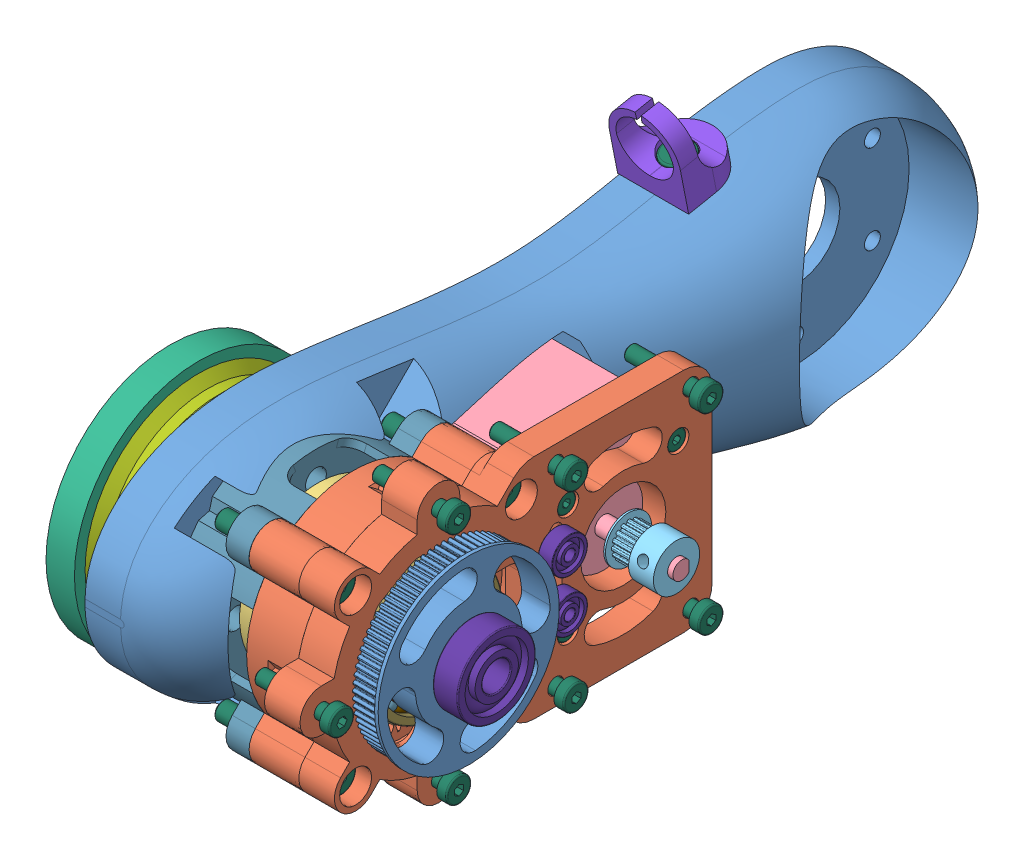
SolidWorks assembly Gelenk_1_V2.0, configuration Standard. Lengths in mm.
Overall size (92 93.85 230.1).
161 component instances, 44 part files, 23 mates.
Components (placement in the parent):
- Gelenk_1_Frame_2.0-2: Gelenk_1_Frame_2.0 [Standard] at origin size (47.61 72.17 230.1)
- G1_Strain_Wave-1: G1_Strain_Wave [Standard] at (47 0 150) x (0 0 -1) z (1 0 0) size (116 78 74.5)
  - G1_Circular_Spline-1: G1_Circular_Spline [Standard] at origin size (116 78 11.48)
  - G1_Flex_Spline-1: G1_Flex_Spline [Standard] at (0 0 -7.5) size (48 48 20)
  - 06153436-1: 06153436 [Default] at (0 0 -32) x (-0.516452 0.856316 0) z (0.856316 0.516452 0) size (37 7 37)
    - 06153436_01-1: 06153436_01 [Default] at origin size (3.6 3.6 3.6)
    - 06153436_02-1: 06153436_02 [Default] at origin size (3.6 3.6 3.6)
    - 06153436_03-1: 06153436_03 [Default] at origin size (3.6 3.6 3.6)
    - 06153436_04-1: 06153436_04 [Default] at origin size (3.6 3.6 3.6)
    - 06153436_05-1: 06153436_05 [Default] at origin size (3.6 3.6 3.6)
    - 06153436_06-1: 06153436_06 [Default] at origin size (3.6 3.6 3.6)
    - 06153436_07-1: 06153436_07 [Default] at origin size (3.6 3.6 3.6)
    - 06153436_08-1: 06153436_08 [Default] at origin size (3.6 3.6 3.6)
    - 06153436_09-1: 06153436_09 [Default] at origin size (3.6 3.6 3.6)
    - 06153436_10-1: 06153436_10 [Default] at origin size (3.6 3.6 3.6)
    - 06153436_11-1: 06153436_11 [Default] at origin size (3.6 3.6 3.6)
    - 06153436_12-1: 06153436_12 [Default] at origin size (3.6 3.6 3.6)
    - 06153436_13-1: 06153436_13 [Default] at origin size (3.6 3.6 3.6)
    - 06153436_14-1: 06153436_14 [Default] at origin size (3.6 3.6 3.6)
    - 06153436_15-1: 06153436_15 [Default] at origin size (3.6 3.6 3.6)
    - 06153436_16-1: 06153436_16 [Default] at origin size (3.6 3.6 3.6)
    - 06153436_17-1: 06153436_17 [Default] at origin size (3.6 3.6 3.6)
    - 06153436_18-1: 06153436_18 [Default] at origin size (3.6 3.6 3.6)
    - 06153436_19-1: 06153436_19 [Default] at origin size (3.6 3.6 3.6)
    - 06153436_20-1: 06153436_20 [Default] at origin size (3.6 3.6 3.6)
    - 06153436_21-1: 06153436_21 [Default] at origin size (3.6 3.6 3.6)
    - 06153436_22-1: 06153436_22 [Default] at origin size (3.6 3.6 3.6)
    - 06153436_23-1: 06153436_23 [Default] at origin size (3.6 3.6 3.6)
    - 06153436_24-1: 06153436_24 [Default] at origin size (3.6 3.6 3.6)
    - 06153436_25-1: 06153436_25 [Default] at origin size (3.6 3.6 3.6)
    - 06153436_26-1: 06153436_26 [Default] at origin size (29.2 7 29.2)
    - 06153436_27-1: 06153436_27 [Default] at origin size (37 7 37)
  - G1_Strain_Wave_Kupplung-1: G1_Strain_Wave_Kupplung [Standard] at (0 0 -35.5) x (-1 0 0) z (0 0 -1) size (26.9 26.9 20)
  - G1_Circular_Spline_Gehaeuse-1: G1_Circular_Spline_Gehaeuse [Standard] at (0 0 -20) size (60 60 22)
  - socket head thin cap screw_din-5: socket head thin cap screw_din [DIN 7984 - M5 x 30 --- 16N] at (23.3345 23.3345 -1.5) x (0 0 -1) z (1 0 0) size (33.5 8.5 8.5)
  - hex nut style 1 gradeab_din-1: hex nut style 1 gradeab_din [Hexagon Nut ISO 4032 - M5 - W - N] at (23.3345 23.3345 -23) x (0.965926 0.258819 0) z (0 0 1) size (8 9.24 4.7)
  - socket head thin cap screw_din-6: socket head thin cap screw_din [DIN 7984 - M5 x 30 --- 16N] at (-23.3345 23.3345 -1.5) x (0 0 -1) z (0 1 0) size (33.5 8.5 8.5)
  - socket head thin cap screw_din-7: socket head thin cap screw_din [DIN 7984 - M5 x 30 --- 16N] at (-23.3345 -23.3345 -1.5) x (0 0 -1) z (-1 0 0) size (33.5 8.5 8.5)
  - socket head thin cap screw_din-8: socket head thin cap screw_din [DIN 7984 - M5 x 30 --- 16N] at (23.3345 -23.3345 -1.5) x (0 0 -1) z (0 -1 0) size (33.5 8.5 8.5)
  - hex nut style 1 gradeab_din-2: hex nut style 1 gradeab_din [Hexagon Nut ISO 4032 - M5 - W - N] at (-23.3345 23.3345 -23) x (-0.258819 0.965926 0) z (0 0 1) size (8 9.24 4.7)
  - hex nut style 1 gradeab_din-3: hex nut style 1 gradeab_din [Hexagon Nut ISO 4032 - M5 - W - N] at (-23.3345 -23.3345 -23) x (-0.965926 -0.258819 0) z (0 0 1) size (8 9.24 4.7)
  - hex nut style 1 gradeab_din-4: hex nut style 1 gradeab_din [Hexagon Nut ISO 4032 - M5 - W - N] at (23.3345 -23.3345 -23) x (0.258819 -0.965926 0) z (0 0 1) size (8 9.24 4.7)
  - radial ball bearing_68_din-1: radial ball bearing_68_din [DIN 625 - 623 - 8,SI,NC,8_68] at (3.1664 -19.2412 -13.368) x (0 0 -1) z (0.167376 0.985893 0) size (4 10 10)
  - hex nut gradec_din-1: hex nut gradec_din [Hexagon Nut ISO 4034 - M5 - N] at (8 0 -46.9) size (8 9.24 5.6)
  - hex nut gradec_din-2: hex nut gradec_din [Hexagon Nut ISO 4034 - M5 - N] at (-8 0 -46.9) size (8 9.24 5.6)
  - 06153436-2: 06153436 [Default] at (0 0 2) x (0.954612 0.297852 0) z (0.297852 -0.954612 0) size (37 7 37)
    - 06153436_01-1: 06153436_01 [Default] at origin size (3.6 3.6 3.6)
    - 06153436_02-1: 06153436_02 [Default] at origin size (3.6 3.6 3.6)
    - 06153436_03-1: 06153436_03 [Default] at origin size (3.6 3.6 3.6)
    - 06153436_04-1: 06153436_04 [Default] at origin size (3.6 3.6 3.6)
    - 06153436_05-1: 06153436_05 [Default] at origin size (3.6 3.6 3.6)
    - 06153436_06-1: 06153436_06 [Default] at origin size (3.6 3.6 3.6)
    - 06153436_07-1: 06153436_07 [Default] at origin size (3.6 3.6 3.6)
    - 06153436_08-1: 06153436_08 [Default] at origin size (3.6 3.6 3.6)
    - 06153436_09-1: 06153436_09 [Default] at origin size (3.6 3.6 3.6)
    - 06153436_10-1: 06153436_10 [Default] at origin size (3.6 3.6 3.6)
    - 06153436_11-1: 06153436_11 [Default] at origin size (3.6 3.6 3.6)
    - 06153436_12-1: 06153436_12 [Default] at origin size (3.6 3.6 3.6)
    - 06153436_13-1: 06153436_13 [Default] at origin size (3.6 3.6 3.6)
    - 06153436_14-1: 06153436_14 [Default] at origin size (3.6 3.6 3.6)
    - 06153436_15-1: 06153436_15 [Default] at origin size (3.6 3.6 3.6)
    - 06153436_16-1: 06153436_16 [Default] at origin size (3.6 3.6 3.6)
    - 06153436_17-1: 06153436_17 [Default] at origin size (3.6 3.6 3.6)
    - 06153436_18-1: 06153436_18 [Default] at origin size (3.6 3.6 3.6)
    - 06153436_19-1: 06153436_19 [Default] at origin size (3.6 3.6 3.6)
    - 06153436_20-1: 06153436_20 [Default] at origin size (3.6 3.6 3.6)
    - 06153436_21-1: 06153436_21 [Default] at origin size (3.6 3.6 3.6)
    - 06153436_22-1: 06153436_22 [Default] at origin size (3.6 3.6 3.6)
    - 06153436_23-1: 06153436_23 [Default] at origin size (3.6 3.6 3.6)
    - 06153436_24-1: 06153436_24 [Default] at origin size (3.6 3.6 3.6)
    - 06153436_25-1: 06153436_25 [Default] at origin size (3.6 3.6 3.6)
    - 06153436_26-1: 06153436_26 [Default] at origin size (29.2 7 29.2)
    - 06153436_27-1: 06153436_27 [Default] at origin size (37 7 37)
  - socket head thin cap screw_din-13: socket head thin cap screw_din [DIN 7984 - M3 x 12 --- 10.5N] at (36.5 15.5 2) x (0 0 -1) z (1 0 0) size (14 5.5 5.5)
  - socket head thin cap screw_din-14: socket head thin cap screw_din [DIN 7984 - M3 x 12 --- 10.5N] at (67.5 15.5 2) x (0 0 -1) z (0 -1 0) size (14 5.5 5.5) (suppressed, hidden)
  - socket head thin cap screw_din-15: socket head thin cap screw_din [DIN 7984 - M3 x 12 --- 10.5N] at (67.5 -15.5 2) x (0 0 -1) z (-1 0 0) size (14 5.5 5.5) (suppressed, hidden)
  - socket head thin cap screw_din-16: socket head thin cap screw_din [DIN 7984 - M3 x 12 --- 10.5N] at (36.5 -15.5 2) x (0 0 -1) z (0 1 0) size (14 5.5 5.5) (suppressed, hidden)
  - G1_Zahnrad_Strain_Wave-1: G1_Zahnrad_Strain_Wave [Standard] at (0 0 3) x (0.49483 -0.86899 0) z (0 0 1) size (51 51 30)
  - radial ball bearing_68_din-3: radial ball bearing_68_din [DIN 625 - 608 - 8,SI,NC,8_68] at (0 0 15.3948) x (0 0 1) z (-0.992451 0.122642 0) size (7 22 22)
  - socket head thin cap screw_din-17: socket head thin cap screw_din [DIN 7984 - M4 x 20 --- 17.9N] at (0 33 8.3) x (0 0 -1) z (1 0 0) size (27.8 7 7)
  - socket head thin cap screw_din-18: socket head thin cap screw_din [DIN 7984 - M4 x 20 --- 17.9N] at (33 27 8.3) x (0 0 -1) z (1 0 0) size (27.8 7 7)
  - hex nut style 1 gradeab_din-9: hex nut style 1 gradeab_din [Hexagon Nut ISO 4032 - M4 - D - N] at (0 33 -6.7) x (1 0 0) z (0 0 -1) size (7 8.08 3.2)
  - hex nut style 1 gradeab_din-10: hex nut style 1 gradeab_din [Hexagon Nut ISO 4032 - M4 - D - N] at (33 27 -4.2) x (1 0 0) z (0 0 -1) size (7 8.08 3.2)
  - socket head thin cap screw_din-19: socket head thin cap screw_din [DIN 7984 - M4 x 20 --- 17.9N] at (-33 0 8.3) x (0 0 -1) z (0 1 0) size (27.8 7 7)
  - socket head thin cap screw_din-20: socket head thin cap screw_din [DIN 7984 - M4 x 20 --- 17.9N] at (0 -33 8.3) x (0 0 -1) z (-1 0 0) size (27.8 7 7)
  - hex nut style 1 gradeab_din-11: hex nut style 1 gradeab_din [Hexagon Nut ISO 4032 - M4 - D - N] at (-33 0 -6.7) x (0 1 0) z (0 0 -1) size (7 8.08 3.2)
  - hex nut style 1 gradeab_din-12: hex nut style 1 gradeab_din [Hexagon Nut ISO 4032 - M4 - D - N] at (0 -33 -6.7) x (-1 0 0) z (0 0 -1) size (7 8.08 3.2)
  - hex nut style 1 gradeab_din-13: hex nut style 1 gradeab_din [Hexagon Nut ISO 4032 - M4 - D - N] at (33 -27 -4.2) x (1 0 0) z (0 0 -1) size (7 8.08 3.2)
  - hex nut style 1 gradeab_din-14: hex nut style 1 gradeab_din [Hexagon Nut ISO 4032 - M4 - D - N] at (71 27 -4.2) x (1 0 0) z (0 0 -1) size (7 8.08 3.2)
  - hex nut style 1 gradeab_din-15: hex nut style 1 gradeab_din [Hexagon Nut ISO 4032 - M4 - D - N] at (71 -27 -4.2) x (1 0 0) z (0 0 -1) size (7 8.08 3.2)
  - socket head thin cap screw_din-21: socket head thin cap screw_din [DIN 7984 - M4 x 20 --- 17.9N] at (33 -27 8.3) x (0 0 -1) z (1 0 0) size (27.8 7 7)
  - socket head thin cap screw_din-22: socket head thin cap screw_din [DIN 7984 - M4 x 20 --- 17.9N] at (71 27 8.3) x (0 0 -1) z (1 0 0) size (27.8 7 7)
  - socket head thin cap screw_din-23: socket head thin cap screw_din [DIN 7984 - M4 x 20 --- 17.9N] at (71 -27 8.3) x (0 0 -1) z (1 0 0) size (27.8 7 7)
  - socket head thin cap screw_din-26: socket head thin cap screw_din [DIN 7984 - M3 x 8 --- 6.5N] at (-8.4059 -10.5043 -19.868) x (0 0 1) z (-1 0 0) size (10 5.5 5.5)
  - socket head thin cap screw_din-27: socket head thin cap screw_din [DIN 7984 - M3 x 8 --- 6.5N] at (-11.3287 7.2568 -19.868) x (0 0 1) z (-1 0 0) size (10 5.5 5.5)
  - G1_Circular_Spline_Teeth-1: G1_Circular_Spline_Teeth [Standard] at origin size (60 60 14)
  - G1_Flex_Spline_Kupplung-1: G1_Flex_Spline_Kupplung [Standard] at (0 0 -27.5) size (44 44 8)
  - socket head thin cap screw_din-28: socket head thin cap screw_din [DIN 7984 - M3 x 8 --- 6.5N] at (0 16 -21.5) x (0 0 -1) z (1 0 0) size (10 5.5 5.5)
  - hex nut style 1 gradeab_din-16: hex nut style 1 gradeab_din [Hexagon Nut ISO 4032 - M3 - D - N] at (0 16 -31.4) x (0 -1 0) z (0 0 -1) size (5.5 6.35 2.4)
  - hex nut style 1 gradeab_din-17: hex nut style 1 gradeab_din [Hexagon Nut ISO 4032 - M3 - D - N] at (-13.8564 8 -31.4) x (0.866025 -0.5 0) z (0 0 -1) size (5.5 6.35 2.4)
  - hex nut style 1 gradeab_din-18: hex nut style 1 gradeab_din [Hexagon Nut ISO 4032 - M3 - D - N] at (-13.8564 -8 -31.4) x (0.866025 0.5 0) z (0 0 -1) size (5.5 6.35 2.4)
  - hex nut style 1 gradeab_din-19: hex nut style 1 gradeab_din [Hexagon Nut ISO 4032 - M3 - D - N] at (0 -16 -31.4) x (0 1 0) z (0 0 -1) size (5.5 6.35 2.4)
  - hex nut style 1 gradeab_din-20: hex nut style 1 gradeab_din [Hexagon Nut ISO 4032 - M3 - D - N] at (13.8564 -8 -31.4) x (-0.866025 0.5 0) z (0 0 -1) size (5.5 6.35 2.4)
  - hex nut style 1 gradeab_din-21: hex nut style 1 gradeab_din [Hexagon Nut ISO 4032 - M3 - D - N] at (13.8564 8 -31.4) x (-0.866025 -0.5 0) z (0 0 -1) size (5.5 6.35 2.4)
  - socket head thin cap screw_din-29: socket head thin cap screw_din [DIN 7984 - M3 x 8 --- 6.5N] at (-13.8564 8 -21.5) x (0 0 -1) z (0.5 0.866025 0) size (10 5.5 5.5)
  - socket head thin cap screw_din-30: socket head thin cap screw_din [DIN 7984 - M3 x 8 --- 6.5N] at (-13.8564 -8 -21.5) x (0 0 -1) z (-0.5 0.866025 0) size (10 5.5 5.5)
  - socket head thin cap screw_din-31: socket head thin cap screw_din [DIN 7984 - M3 x 8 --- 6.5N] at (0 -16 -21.5) x (0 0 -1) z (-1 0 0) size (10 5.5 5.5)
  - socket head thin cap screw_din-32: socket head thin cap screw_din [DIN 7984 - M3 x 8 --- 6.5N] at (13.8564 -8 -21.5) x (0 0 -1) z (-0.5 -0.866025 0) size (10 5.5 5.5)
  - socket head thin cap screw_din-33: socket head thin cap screw_din [DIN 7984 - M3 x 8 --- 6.5N] at (13.8564 8 -21.5) x (0 0 -1) z (0.5 -0.866025 0) size (10 5.5 5.5)
  - socket head thin cap screw_din-34: socket head thin cap screw_din [DIN 7984 - M3 x 16 --- 14.5N] at (7.0711 7.0711 -25.5) x (0 0 -1) z (1 0 0) size (18 5.5 5.5)
  - hex nut style 1 gradeab_din-22: hex nut style 1 gradeab_din [Hexagon Nut ISO 4032 - M3 - D - N] at (7.0711 7.0711 -42.9) x (0.258819 0.965926 0) z (0 0 -1) size (5.5 6.35 2.4)
  - hex nut style 1 gradeab_din-23: hex nut style 1 gradeab_din [Hexagon Nut ISO 4032 - M3 - D - N] at (-7.0711 7.0711 -42.9) x (-0.965926 0.258819 0) z (0 0 -1) size (5.5 6.35 2.4)
  - hex nut style 1 gradeab_din-24: hex nut style 1 gradeab_din [Hexagon Nut ISO 4032 - M3 - D - N] at (-7.0711 -7.0711 -42.9) x (-0.258819 -0.965926 0) z (0 0 -1) size (5.5 6.35 2.4)
  - hex nut style 1 gradeab_din-25: hex nut style 1 gradeab_din [Hexagon Nut ISO 4032 - M3 - D - N] at (7.0711 -7.0711 -42.9) x (0.965926 -0.258819 0) z (0 0 -1) size (5.5 6.35 2.4)
  - socket head thin cap screw_din-35: socket head thin cap screw_din [DIN 7984 - M3 x 16 --- 14.5N] at (-7.0711 7.0711 -25.5) x (0 0 -1) z (0 1 0) size (18 5.5 5.5)
  - socket head thin cap screw_din-36: socket head thin cap screw_din [DIN 7984 - M3 x 16 --- 14.5N] at (-7.0711 -7.0711 -25.5) x (0 0 -1) z (-1 0 0) size (18 5.5 5.5)
  - socket head thin cap screw_din-37: socket head thin cap screw_din [DIN 7984 - M3 x 16 --- 14.5N] at (7.0711 -7.0711 -25.5) x (0 0 -1) z (0 -1 0) size (18 5.5 5.5)
  - socket head thin cap screw_din-38: socket head thin cap screw_din [DIN 7984 - M3 x 12 --- 10.5N] at (36.5 -15.5 2) x (0 0 -1) z (0 1 0) size (14 5.5 5.5)
  - socket head thin cap screw_din-39: socket head thin cap screw_din [DIN 7984 - M3 x 12 --- 10.5N] at (67.5 -15.5 2) x (0 0 -1) z (-1 0 0) size (14 5.5 5.5)
  - socket head thin cap screw_din-40: socket head thin cap screw_din [DIN 7984 - M3 x 12 --- 10.5N] at (67.5 15.5 2) x (0 0 -1) z (0 -1 0) size (14 5.5 5.5)
  - Nema_17_48mm-1: Nema_17_48mm [Default] at (52 0 -54) x (1 0 0) z (0 -1 0) size (42 73 42)
  - hex nut style 1 gradeab_din-27: hex nut style 1 gradeab_din [Hexagon Nut ISO 4032 - M3 - D - N] at (33 6.8674 -1) x (0.5 0.866025 0) z (0 0 1) size (5.5 6.35 2.4)
  - Zahnriemenscheibe_Base_Motor-1: Zahnriemenscheibe_Base_Motor [Standard] at (52 0 17.5) x (-0.399354 -0.916797 0) z (0.916797 -0.399354 0) size (13 14 13)
  - radial ball bearing_68_din-5: radial ball bearing_68_din [DIN 625 - 623 - 8,SI,NC,8_68] at (33 6.8674 4.5) x (0 0 -1) z (-0.991555 0.129691 0) size (4 10 10)
  - radial ball bearing_68_din-6: radial ball bearing_68_din [DIN 625 - 623 - 8,SI,NC,8_68] at (33 -7.6886 4.5) x (0 0 -1) z (-0.829843 0.557997 0) size (4 10 10)
- 06153436-1: 06153436 [Default] at (-10 0 150) x (0 0.996792 -0.080037) z (0 0.080037 0.996792) size (37 7 37)
  - 06153436_01-1: 06153436_01 [Default] at origin size (3.6 3.6 3.6)
  - 06153436_02-1: 06153436_02 [Default] at origin size (3.6 3.6 3.6)
  - 06153436_03-1: 06153436_03 [Default] at origin size (3.6 3.6 3.6)
  - 06153436_04-1: 06153436_04 [Default] at origin size (3.6 3.6 3.6)
  - 06153436_05-1: 06153436_05 [Default] at origin size (3.6 3.6 3.6)
  - 06153436_06-1: 06153436_06 [Default] at origin size (3.6 3.6 3.6)
  - 06153436_07-1: 06153436_07 [Default] at origin size (3.6 3.6 3.6)
  - 06153436_08-1: 06153436_08 [Default] at origin size (3.6 3.6 3.6)
  - 06153436_09-1: 06153436_09 [Default] at origin size (3.6 3.6 3.6)
  - 06153436_10-1: 06153436_10 [Default] at origin size (3.6 3.6 3.6)
  - 06153436_11-1: 06153436_11 [Default] at origin size (3.6 3.6 3.6)
  - 06153436_12-1: 06153436_12 [Default] at origin size (3.6 3.6 3.6)
  - 06153436_13-1: 06153436_13 [Default] at origin size (3.6 3.6 3.6)
  - 06153436_14-1: 06153436_14 [Default] at origin size (3.6 3.6 3.6)
  - 06153436_15-1: 06153436_15 [Default] at origin size (3.6 3.6 3.6)
  - 06153436_16-1: 06153436_16 [Default] at origin size (3.6 3.6 3.6)
  - 06153436_17-1: 06153436_17 [Default] at origin size (3.6 3.6 3.6)
  - 06153436_18-1: 06153436_18 [Default] at origin size (3.6 3.6 3.6)
  - 06153436_19-1: 06153436_19 [Default] at origin size (3.6 3.6 3.6)
  - 06153436_20-1: 06153436_20 [Default] at origin size (3.6 3.6 3.6)
  - 06153436_21-1: 06153436_21 [Default] at origin size (3.6 3.6 3.6)
  - 06153436_22-1: 06153436_22 [Default] at origin size (3.6 3.6 3.6)
  - 06153436_23-1: 06153436_23 [Default] at origin size (3.6 3.6 3.6)
  - 06153436_24-1: 06153436_24 [Default] at origin size (3.6 3.6 3.6)
  - 06153436_25-1: 06153436_25 [Default] at origin size (3.6 3.6 3.6)
  - 06153436_26-1: 06153436_26 [Default] at origin size (29.2 7 29.2)
  - 06153436_27-1: 06153436_27 [Default] at origin size (37 7 37)
- Kupplungsscheibe-1: Kupplungsscheibe [Standard] at (-18 0 150) x (-1 0 0) z (0 0 -1) size (26.5 70 70)
- Gelenk_1_Kugellager_Halter-1: Gelenk_1_Kugellager_Halter [Standard] at (-18 0 150) x (0 0 -1) z (1 0 0) size (70 70 8)
- socket head thin cap screw_din-1: socket head thin cap screw_din [DIN 7984 - M3 x 20 --- 12N] at (-16.5 15.5 165.5) size (22 5.5 5.5)
- socket head thin cap screw_din-2: socket head thin cap screw_din [DIN 7984 - M3 x 20 --- 12N] at (-16.5 15.5 134.5) x (1 0 0) z (0 1 0) size (22 5.5 5.5)
- socket head thin cap screw_din-3: socket head thin cap screw_din [DIN 7984 - M3 x 20 --- 12N] at (-16.5 -15.5 134.5) x (1 0 0) z (0 0 -1) size (22 5.5 5.5)
- socket head thin cap screw_din-4: socket head thin cap screw_din [DIN 7984 - M3 x 20 --- 12N] at (-16.5 -15.5 165.5) x (1 0 0) z (0 -1 0) size (22 5.5 5.5)
- Kabelklemme-1: Kabelklemme [Standard] at (0 31.3392 32.2226) x (1 0 0) z (0 -0.192812 0.981236) size (20 21.99 18)
- socket head thin cap screw_din-5: socket head thin cap screw_din [DIN 7984 - M5 x 10 --- 7.6N] at (0 36.736 33.2831) x (0 -0.981236 -0.192812) z (0.192812 -0.189194 0.962823) size (13.5 8.5 8.5)
Mates (geometry in assembly coordinates):
- Deckungsgleich4: coincident aligned: plane of Gelenk_1_Frame_2.0-2 through (0 0 0) normal (0 0 1)
- Deckungsgleich5: coincident aligned: plane of Gelenk_1_Frame_2.0-2 through (0 0 0) normal (0 1 0)
- Deckungsgleich6: coincident aligned: plane of Gelenk_1_Frame_2.0-2 through (0 0 0) normal (1 0 0)
- Konzentrisch1: concentric aligned: cylinder of Gelenk_1_Frame_2.0-2 through (37.5619 15.5 134.5) axis (-1 0 0) radius 1.75; cylinder of G1_Strain_Wave-1/G1_Circular_Spline_Gehaeuse-1 through (27 15.5 134.5) axis (-1 0 0) radius 1.5
- Konzentrisch2: concentric aligned: cylinder of Gelenk_1_Frame_2.0-2 through (37.5619 -15.5 165.5) axis (-1 0 0) radius 1.75; cylinder of G1_Strain_Wave-1/G1_Circular_Spline_Gehaeuse-1 through (27 -15.5 165.5) axis (-1 0 0) radius 1.5
- Konzentrisch3: concentric aligned: cylinder of Gelenk_1_Frame_2.0-2 through (-3 0 150) axis (-1 0 0) radius 18.65; cylinder of 06153436-1/06153436_27-1 through (-6.5 0 150) axis (-1 0 0) radius 18.5
- Deckungsgleich7: coincident anti-aligned: plane of Gelenk_1_Frame_2.0-2 through (-3 0 150) normal (-1 0 0); plane of 06153436-1/06153436_27-1 through (-3 1.3846 167.2445) normal (1 0 0)
- Konzentrisch4: concentric aligned: cylinder of G1_Strain_Wave-1/G1_Strain_Wave_Kupplung-1 through (11.5 0 142) axis (-1 0 0) radius 2.75; cylinder of Kupplungsscheibe-1 through (-8 0 142) axis (-1 0 0) radius 2.5
- Konzentrisch5: concentric aligned: cylinder of G1_Strain_Wave-1/G1_Strain_Wave_Kupplung-1 through (11.5 0 158) axis (-1 0 0) radius 2.75; cylinder of Kupplungsscheibe-1 through (-8 0 158) axis (-1 0 0) radius 2.5
- Konzentrisch6: concentric aligned: cylinder of Gelenk_1_Frame_2.0-2 through (37.5619 15.5 134.5) axis (-1 0 0) radius 1.75; cylinder of Gelenk_1_Kugellager_Halter-1 through (-10 15.5 134.5) axis (-1 0 0) radius 1.75
- Konzentrisch7: concentric aligned: cylinder of Gelenk_1_Frame_2.0-2 through (37.5619 -15.5 165.5) axis (-1 0 0) radius 1.75; cylinder of Gelenk_1_Kugellager_Halter-1 through (-10 -15.5 165.5) axis (-1 0 0) radius 1.75
- Konzentrisch8: concentric aligned: cylinder of Gelenk_1_Kugellager_Halter-1 through (-10 15.5 165.5) axis (-1 0 0) radius 1.75; cylinder of socket head thin cap screw_din-1 through (-48.25 15.5 165.5) axis (-1 0 0) radius 2.75
- Deckungsgleich9: coincident anti-aligned: plane of Gelenk_1_Kugellager_Halter-1 through (-14.5 15.5 165.5) normal (-1 0 0); plane of socket head thin cap screw_din-1 through (-14.5 18.25 165.5) normal (1 0 0)
- Deckungsgleich10: coincident anti-aligned: plane of Kupplungsscheibe-1 through (-18 0 150) normal (1 0 0); plane of Gelenk_1_Kugellager_Halter-1 through (-18 0 150) normal (-1 0 0)
- Konzentrisch9: concentric aligned: cylinder of Gelenk_1_Frame_2.0-2 through (37.5619 15.5 134.5) axis (-1 0 0) radius 1.75; cylinder of G1_Strain_Wave-1/G1_Circular_Spline_Gehaeuse-1 through (27 15.5 134.5) axis (-1 0 0) radius 1.5
- Konzentrisch10: concentric aligned: cylinder of Gelenk_1_Frame_2.0-2 through (37.5619 -15.5 165.5) axis (-1 0 0) radius 1.75; cylinder of G1_Strain_Wave-1/G1_Circular_Spline_Gehaeuse-1 through (27 -15.5 165.5) axis (-1 0 0) radius 1.5
- Deckungsgleich11: coincident anti-aligned: plane of Gelenk_1_Frame_2.0-2 through (5 -25.6263 87.3193) normal (1 0 0); plane of G1_Strain_Wave-1/G1_Circular_Spline_Gehaeuse-1 through (5 14 150) normal (-1 0 0)
- Deckungsgleich12: coincident anti-aligned: plane of Gelenk_1_Frame_2.0-2 through (-10 -25.6263 87.3193) normal (-1 0 0); plane of Gelenk_1_Kugellager_Halter-1 through (-10 0 150) normal (1 0 0)
- Konzentrisch11: concentric aligned: cylinder of Gelenk_1_Frame_2.0-2 through (0 65.7693 38.9881) axis (0 -0.981236 -0.192812) radius 2.45; cylinder of Kabelklemme-1 through (0 36.2454 33.1867) axis (0 -0.981236 -0.192812) radius 2.75
- Abstand1: distance = 10.5 mm anti-aligned: plane of Kabelklemme-1 through (0 31.3392 32.2226) normal (0 -0.981236 -0.192812); plane of Gelenk_1_Frame_2.0-2 through (0 21.0362 30.1981) normal (0 0.981236 0.192812)
- Parallel1: parallel aligned: plane of Gelenk_1_Frame_2.0-2 through (-10 -25.6263 87.3193) normal (-1 0 0); plane of Kabelklemme-1 through (-10 36.2454 33.1867) normal (-1 0 0)
- Konzentrisch12: concentric anti-aligned: cylinder of Kabelklemme-1 through (0 36.2454 33.1867) axis (0 -0.981236 -0.192812) radius 2.75; cylinder of socket head thin cap screw_din-5 through (0 67.8902 39.4049) axis (0 0.981236 0.192812) radius 4.25
- Deckungsgleich15: coincident anti-aligned: plane of Kabelklemme-1 through (0 33.3017 32.6082) normal (0 0.981236 0.192812); plane of socket head thin cap screw_din-5 through (4.1703 33.4597 31.8042) normal (0 -0.981236 -0.192812)
